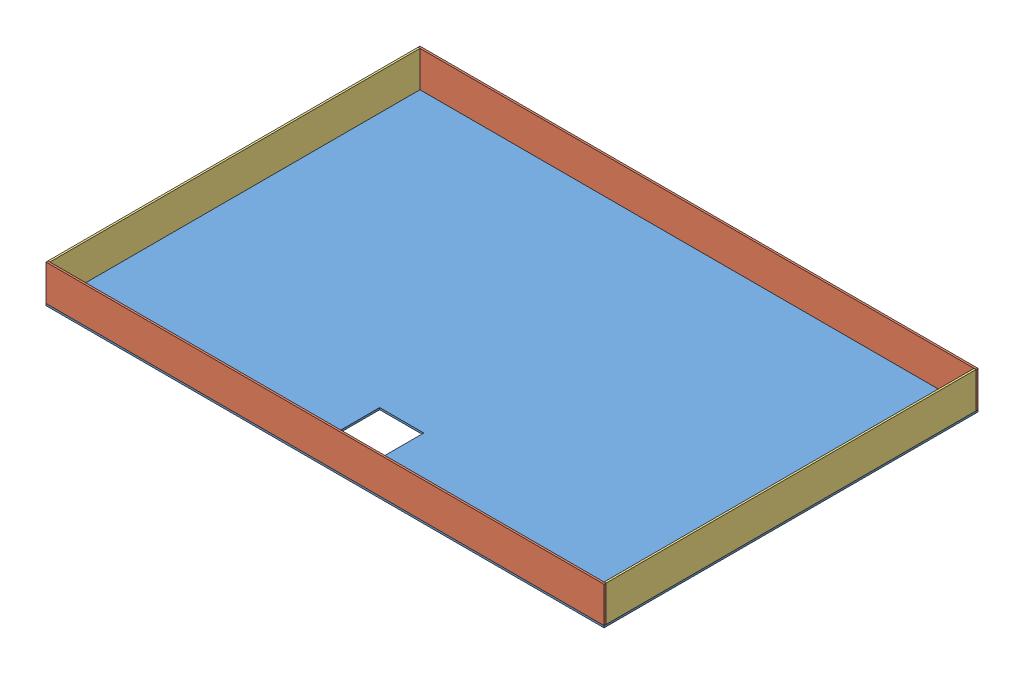
SolidWorks assembly tableTopper_Assembly_v1, configuration Default. Lengths in mm.
Overall size (923.92 62.57 619.12).
5 component instances, 3 part files, 30 mates.
Components (placement in the parent):
- tableTopper_top_v1-1: tableTopper_top_v1 [Default] at (-525.1873 9.6187 335.3121) size (923.92 3.17 619.12)
- tableTopper_longRail_v1-1: tableTopper_longRail_v1 [Default] at (-525.1873 12.7937 332.1371) x (1 0 0) z (0 -1 0) size (923.92 3.17 59.4)
- tableTopper_longRail_v1-2: tableTopper_longRail_v1 [Default] at (-525.1873 12.7937 -283.8129) x (1 0 0) z (0 -1 0) size (923.92 3.17 59.4)
- tableTopper_shortRail_v1-1: tableTopper_shortRail_v1 [Default] at (-525.1873 12.7937 332.1371) x (0 0 -1) z (0 -1 0) size (612.77 3.17 59.4)
- tableTopper_shortRail_v1-2: tableTopper_shortRail_v1 [Default] at (398.7377 12.7937 -280.6379) x (0 0 1) z (0 -1 0) size (612.77 3.17 59.4)
Mates (geometry in assembly coordinates):
- Coincident1: coincident anti-aligned: plane of tableTopper_top_v1-1 through (-525.1873 12.7937 335.3121) normal (0 1 0); plane of tableTopper_p3_v1-1 through (-522.0123 12.7937 332.1371) normal (0 -1 0)
- Coincident2: coincident anti-aligned: plane of tableTopper_top_v1-1 through (-525.1873 12.7937 335.3121) normal (0 1 0); plane of tableTopper_p3_v1-2 through (395.5627 12.7937 -280.6379) normal (0 -1 0)
- Coincident3: coincident anti-aligned: plane of tableTopper_top_v1-1 through (-525.1873 12.7937 335.3121) normal (0 1 0); plane of tableTopper_p2_v1-2 through (-525.1873 12.7937 -280.6379) normal (0 -1 0)
- Coincident4: coincident anti-aligned: plane of tableTopper_top_v1-1 through (-525.1873 12.7937 335.3121) normal (0 1 0); plane of tableTopper_p2_v1-1 through (-525.1873 12.7937 335.3121) normal (0 -1 0)
- Coincident5: coincident aligned: plane of tableTopper_top_v1-1 through (-525.1873 12.7937 335.3121) normal (0 0 1); plane of tableTopper_p2_v1-1 through (-525.1873 12.7937 335.3121) normal (0 0 1)
- Coincident6: coincident aligned: plane of tableTopper_top_v1-1 through (-525.1873 12.7937 -283.8129) normal (0 0 -1); plane of tableTopper_p2_v1-2 through (-525.1873 12.7937 -283.8129) normal (0 0 -1)
- Coincident7: coincident aligned: plane of tableTopper_top_v1-1 through (398.7377 12.7937 335.3121) normal (1 0 0); plane of tableTopper_p3_v1-2 through (398.7377 12.7937 -280.6379) normal (1 0 0)
- Coincident8: coincident aligned: plane of tableTopper_top_v1-1 through (-525.1873 12.7937 335.3121) normal (-1 0 0); plane of tableTopper_p3_v1-1 through (-525.1873 12.7937 332.1371) normal (-1 0 0)
- Coincident9: coincident aligned: plane of tableTopper_top_v1-1 through (-525.1873 12.7937 335.3121) normal (-1 0 0); plane of tableTopper_p2_v1-1 through (-525.1873 12.7937 335.3121) normal (-1 0 0)
- Coincident10: coincident aligned: plane of tableTopper_top_v1-1 through (-525.1873 12.7937 335.3121) normal (-1 0 0); plane of tableTopper_p2_v1-2 through (-525.1873 12.7937 -280.6379) normal (-1 0 0)
- Coincident11: coincident anti-aligned: plane of tableTopper_p2_v1-2 through (-525.1873 12.7937 -280.6379) normal (0 0 1); plane of tableTopper_p3_v1-1 through (-522.0123 12.7937 -280.6379) normal (0 0 -1)
- Coincident12: coincident anti-aligned: plane of tableTopper_p2_v1-2 through (-525.1873 12.7937 -280.6379) normal (0 0 1); plane of tableTopper_p3_v1-2 through (395.5627 12.7937 -280.6379) normal (0 0 -1)
- Coincident13: coincident anti-aligned: plane of tableTopper_top_v1-1 through (-525.1873 12.7937 335.3121) normal (0 1 0); plane of tableTopper_longSlat_v1-1 through (-522.0123 12.7937 119.9807) normal (0 -1 0)
- Coincident14: coincident anti-aligned: plane of tableTopper_top_v1-1 through (-525.1873 12.7937 335.3121) normal (0 1 0); plane of tableTopper_longSlat_v1-2 through (-522.0123 12.7937 -102.2997) normal (0 -1 0)
- Coincident15: coincident anti-aligned: plane of tableTopper_top_v1-1 through (-525.1873 12.7937 335.3121) normal (0 1 0); plane of tableTopper_shortRail_v1-4 through (99.7028 12.7937 332.1371) normal (0 -1 0)
- Coincident16: coincident anti-aligned: plane of tableTopper_top_v1-1 through (-525.1873 12.7937 335.3121) normal (0 1 0); plane of tableTopper_shortRail_v1-3 through (-186.8359 12.7937 332.1371) normal (0 -1 0)
- Parallel1: parallel aligned: plane of tableTopper_longRail_v1-1 through (-525.1873 12.7937 335.3121) normal (0 0 1); plane of tableTopper_longSlat_v1-1 through (-522.0123 12.7937 119.9807) normal (0 0 1)
- Parallel2: parallel aligned: plane of tableTopper_longRail_v1-1 through (-525.1873 12.7937 335.3121) normal (0 0 1); plane of tableTopper_longSlat_v1-2 through (-522.0123 12.7937 -102.2997) normal (0 0 1)
- Parallel3: parallel aligned: plane of tableTopper_shortRail_v1-2 through (398.7377 12.7937 -280.6379) normal (1 0 0); plane of tableTopper_shortRail_v1-4 through (99.7028 12.7937 332.1371) normal (1 0 0)
- Parallel4: parallel aligned: plane of tableTopper_shortRail_v1-2 through (398.7377 12.7937 -280.6379) normal (1 0 0); plane of tableTopper_shortRail_v1-3 through (-186.8359 12.7937 332.1371) normal (1 0 0)
- Coincident22: coincident anti-aligned: plane of tableTopper_shortRail_v1-2 through (395.5627 12.7937 -280.6379) normal (-1 0 0); plane of tableTopper_longSlat_v1-1 through (395.5627 12.7937 119.9807) normal (1 0 0)
- Coincident23: coincident anti-aligned: plane of tableTopper_shortRail_v1-2 through (395.5627 12.7937 -280.6379) normal (-1 0 0); plane of tableTopper_longSlat_v1-2 through (395.5627 12.7937 -102.2997) normal (1 0 0)
- Coincident24: coincident anti-aligned: plane of tableTopper_longRail_v1-1 through (-525.1873 12.7937 332.1371) normal (0 0 -1); plane of tableTopper_shortRail_v1-3 through (-186.8359 12.7937 332.1371) normal (0 0 1)
- Coincident25: coincident anti-aligned: plane of tableTopper_longRail_v1-1 through (-525.1873 12.7937 332.1371) normal (0 0 -1); plane of tableTopper_shortRail_v1-4 through (99.7028 12.7937 332.1371) normal (0 0 1)
- Coincident26: coincident anti-aligned: plane of tableTopper_top_v1-1 through (-525.1873 12.7937 335.3121) normal (0 1 0); plane of tableTopper_shortSlat_v1-2 through (-208.4782 12.7937 332.1371) normal (0 -1 0)
- Coincident27: coincident anti-aligned: plane of tableTopper_top_v1-1 through (-525.1873 12.7937 335.3121) normal (0 1 0); plane of tableTopper_shortSlat_v1-1 through (-44.0342 12.7937 332.1371) normal (0 -1 0)
- Parallel5: parallel anti-aligned: plane of tableTopper_shortRail_v1-1 through (-525.1873 12.7937 332.1371) normal (-1 0 0); plane of tableTopper_shortSlat_v1-2 through (-208.4782 12.7937 332.1371) normal (1 0 0)
- Parallel6: parallel anti-aligned: plane of tableTopper_shortRail_v1-1 through (-525.1873 12.7937 332.1371) normal (-1 0 0); plane of tableTopper_shortSlat_v1-1 through (-44.0342 12.7937 332.1371) normal (1 0 0)
- Coincident28: coincident anti-aligned: plane of tableTopper_longRail_v1-1 through (-525.1873 12.7937 332.1371) normal (0 0 -1); plane of tableTopper_shortSlat_v1-1 through (-44.0342 12.7937 332.1371) normal (0 0 1)
- Coincident29: coincident anti-aligned: plane of tableTopper_longRail_v1-1 through (-525.1873 12.7937 332.1371) normal (0 0 -1); plane of tableTopper_shortSlat_v1-2 through (-208.4782 12.7937 332.1371) normal (0 0 1)
